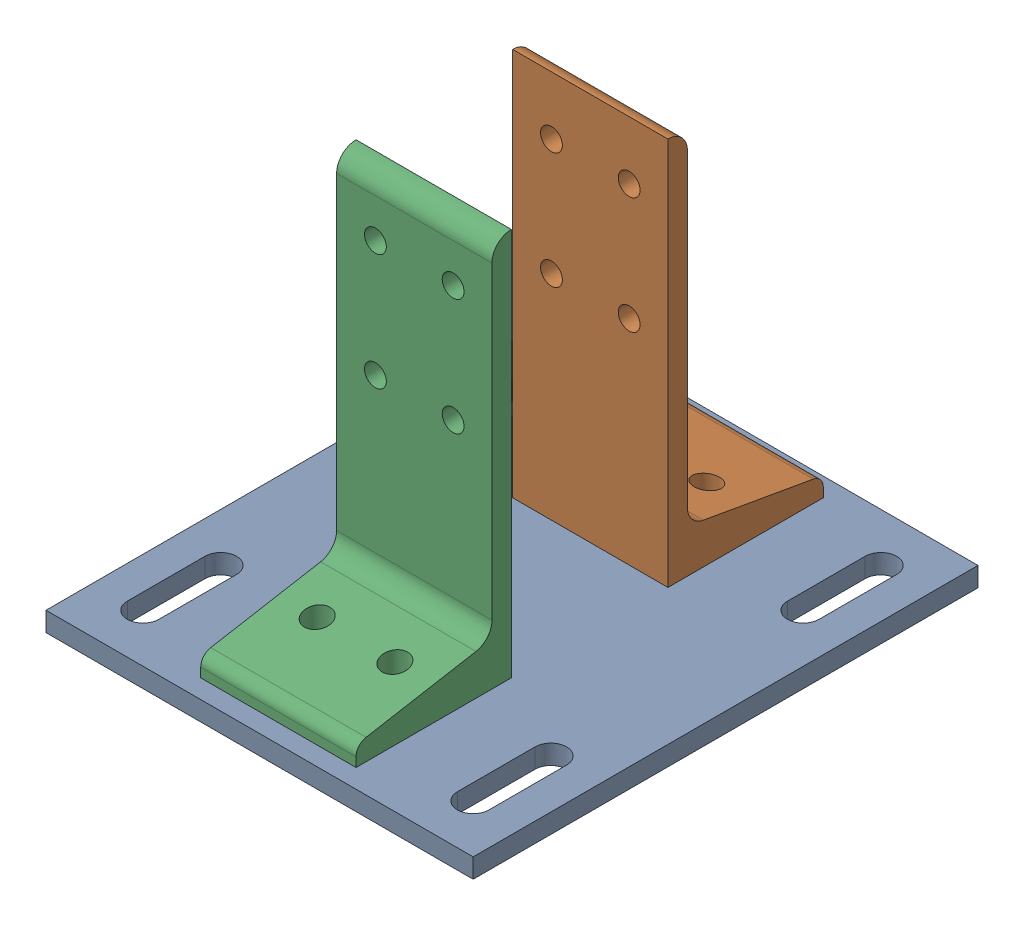
SolidWorks assembly Mirror8020-2387-DEFAULT3, configuration Default. Lengths in mm.
Overall size (139.7 133.35 165.1).
3 component instances, 2 part files, 0 mates.
Components (placement in the parent):
- Mirror8020-2387-DEFAULT_238708-1: Mirror8020-2387-DEFAULT_238708 [Default] at (-67.1549 7.3704 -27.8119) size (139.7 6.35 165.1)
- Mirror8020-2387-DEFAULT_238509-1: Mirror8020-2387-DEFAULT_238509 [Default] at (9.1264 0.0214 -49.7635) x (0 0 -1) z (1 0 0) size (50.8 127 50.8)
- Mirror8020-2387-DEFAULT_238509-2: Mirror8020-2387-DEFAULT_238509 [Default] at (-41.6736 0.0214 46.9187) x (0 0 1) z (-1 0 0) size (50.8 127 50.8)
